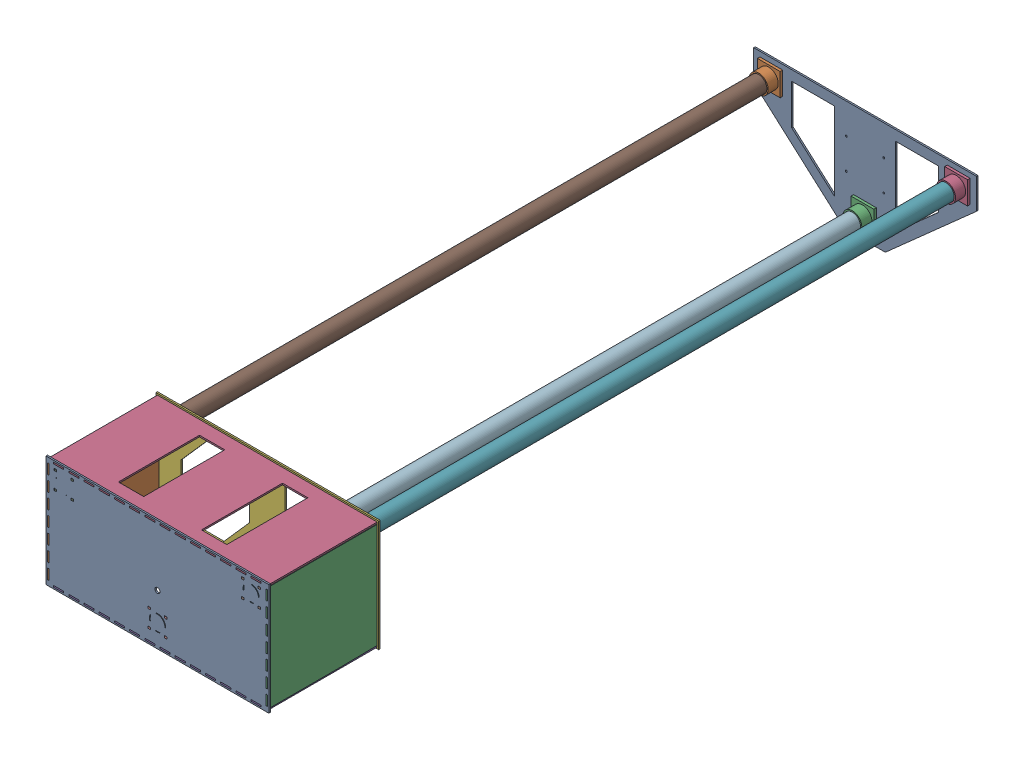
SolidWorks assembly AssembFinal, configuration Défaut. Lengths in mm.
Overall size (440.4 220 1400).
16 component instances, 8 part files, 31 mates.
Components (placement in the parent):
- Base_Boite-1: Base_Boite [Défaut] at (-19.2161 6.3272 0) size (440 220 3)
- CôtéDG_Boite-1: CôtéDG_Boite [Défaut] at (-236.2161 5.3272 -107) x (0 1 0) z (1 0 0) size (208 220 3)
- CôtéDG_Boite-2: CôtéDG_Boite [Défaut] at (197.7839 5.3272 -107) x (0 1 0) z (-1 0 0) size (208 220 3)
- Côté_Arrière_Boite-1: Côté_Arrière_Boite [Défaut] at (-19.2161 113.3272 -107) x (1 0 0) z (0 -1 0) size (434 220 3)
- Côté_Arrière_Boite_ecran-1: Côté_Arrière_Boite_ecran [Défaut] at (-19.2161 -97.6728 -107) x (1 0 0) z (0 -1 0) size (434 220 3)
- Toit_Boite-1: Toit_Boite [Défaut] at (-19.2161 6.3272 -217) size (440 220 3)
- Tube_PVC-1: Tube_PVC [Défaut] at (165.7839 84.1272 -1397) x (-0.09486 0.995491 0) z (0 0 1) size (32 32 1400)
- Support_Tube-2: Support_Tube [Défaut] at (165.7839 84.1272 0) x (1 0 0) z (0 0 -1) size (45 45 28)
- Support_Tube-3: Support_Tube [Défaut] at (-204.0161 84.1272 0) x (1 0 0) z (0 0 -1) size (45 45 28)
- Support_Tube-4: Support_Tube [Défaut] at (-19.0161 -58.8728 0) x (1 0 0) z (0 0 -1) size (45 45 28)
- Tube_PVC-2: Tube_PVC [Défaut] at (-204.0161 84.1272 -1397) x (-0.93972 0.341944 0) z (0 0 1) size (32 32 1400)
- Tube_PVC-3: Tube_PVC [Défaut] at (-19.0161 -58.8728 -1397) x (-0.80011 0.599853 0) z (0 0 1) size (32 32 1400)
- Toit_Zone_Calcul-1: Toit_Zone_Calcul [Défaut] at (-18.8161 6.3272 -1394) x (-1 0 0) z (0 0 -1) size (440 220 3)
- Support_Tube-6: Support_Tube [Défaut] at (-204.0161 84.1272 -1394) x (-1 0 0) z (0 0 1) size (45 45 28)
- Support_Tube-7: Support_Tube [Défaut] at (-19.0161 -58.8728 -1394) x (-1 0 0) z (0 0 1) size (45 45 28)
- Support_Tube-8: Support_Tube [Défaut] at (165.9839 84.1272 -1394) x (-1 0 0) z (0 0 1) size (45 45 28)
Mates (geometry in assembly coordinates):
- Coïncidente1: coincident anti-aligned: line of Base_Boite-1 through (-233.2161 106.3272 3) axis (-1 0 0); line of CôtéDG_Boite-1 through (-236.2161 106.3272 3) axis (1 0 0)
- Coïncidente2: coincident anti-aligned: line of Base_Boite-1 through (-233.2161 86.3272 3) axis (0 1 0); line of CôtéDG_Boite-1 through (-233.2161 106.3272 3) axis (0 -1 0)
- Coïncidente6: coincident anti-aligned: line of Base_Boite-1 through (194.7839 -93.6728 3) axis (1 0 0); line of CôtéDG_Boite-2 through (197.7839 -93.6728 3) axis (-1 0 0)
- Coïncidente7: coincident anti-aligned: line of Base_Boite-1 through (194.7839 -73.6728 3) axis (0 -1 0); line of CôtéDG_Boite-2 through (194.7839 -93.6728 3) axis (0 1 0)
- Coïncidente8: coincident anti-aligned: line of Base_Boite-1 through (185.7839 110.3272 3) axis (0 1 0); line of Côté_Arrière_Boite-1 through (185.7839 113.3272 3) axis (0 -1 0)
- Coïncidente10: coincident anti-aligned: line of Base_Boite-1 through (165.7839 110.3272 3) axis (1 0 0); line of Côté_Arrière_Boite-1 through (185.7839 110.3272 3) axis (-1 0 0)
- Coïncidente11: coincident aligned: line of Base_Boite-1 through (-224.2161 -97.6728 3) axis (0 -1 0); line of Côté_Arrière_Boite_ecran-1 through (-224.2161 -97.6728 3) axis (0 -1 0)
- Coïncidente12: coincident aligned: line of Base_Boite-1 through (-204.2161 -97.6728 3) axis (-1 0 0); line of Côté_Arrière_Boite_ecran-1 through (-204.2161 -97.6728 3) axis (-1 0 0)
- Coïncidente13: coincident anti-aligned: line of Côté_Arrière_Boite_ecran-1 through (-224.2161 -97.6728 -217) axis (0 -1 0); line of Toit_Boite-1 through (-224.2161 -100.6728 -217) axis (0 1 0)
- Coïncidente15: coincident aligned: line of Côté_Arrière_Boite_ecran-1 through (-224.2161 -97.6728 -217) axis (1 0 0); line of Toit_Boite-1 through (-224.2161 -97.6728 -217) axis (1 0 0)
- Coïncidente18: coincident aligned: line of Base_Boite-1 through (179.7839 65.3272 3) axis (1 0 0); line of Support_Tube-2 through (179.7839 65.3272 3) axis (1 0 0)
- Coïncidente19: coincident aligned: line of Base_Boite-1 through (179.7839 69.3272 3) axis (0 -1 0); line of Support_Tube-2 through (179.7839 69.1272 3) axis (0 -1 0)
- Coïncidente20: coincident aligned: line of Base_Boite-1 through (-190.2161 65.3272 3) axis (1 0 0); line of Support_Tube-3 through (-190.0161 65.3272 3) axis (1 0 0)
- Coïncidente21: coincident aligned: line of Base_Boite-1 through (-185.2161 65.3272 3) axis (0 1 0); line of Support_Tube-3 through (-185.2161 65.3272 3) axis (0 1 0)
- Coïncidente22: coincident aligned: line of Base_Boite-1 through (-5.2161 -77.6728 3) axis (1 0 0); line of Support_Tube-4 through (-5.0161 -77.6728 3) axis (1 0 0)
- Coïncidente23: coincident aligned: line of Base_Boite-1 through (-0.2161 -77.6728 3) axis (0 1 0); line of Support_Tube-4 through (-0.2161 -77.6728 3) axis (0 1 0)
- Coaxiale1: concentric anti-aligned: circle of Tube_PVC-1; circle of Support_Tube-2
- Coaxiale2: concentric aligned: cylinder of Support_Tube-3 through (-204.0161 84.1272 -5) axis (0 0 1) radius 16.25; circle of Tube_PVC-2
- Coaxiale3: concentric anti-aligned: circle of Support_Tube-4; circle of Tube_PVC-3
- Coïncidente24: coincident aligned: plane of Base_Boite-1 through (-19.2161 6.3272 3) normal (0 0 1); circle of Tube_PVC-1
- Coïncidente25: coincident aligned: plane of Base_Boite-1 through (-19.2161 6.3272 3) normal (0 0 1); circle of Tube_PVC-2
- Coïncidente26: coincident aligned: plane of Base_Boite-1 through (-19.2161 6.3272 3) normal (0 0 1); circle of Tube_PVC-3
- Coïncidente37: coincident anti-aligned: line of Toit_Zone_Calcul-1 through (-222.8161 65.3272 -1397) axis (1 0 0); line of Support_Tube-6 through (-218.0161 65.3272 -1397) axis (-1 0 0)
- Coïncidente38: coincident anti-aligned: line of Toit_Zone_Calcul-1 through (-222.8161 69.3272 -1397) axis (0 -1 0); line of Support_Tube-6 through (-222.8161 65.3272 -1397) axis (0 1 0)
- Coïncidente39: coincident anti-aligned: line of Toit_Zone_Calcul-1 through (-37.8161 -77.6728 -1397) axis (1 0 0); line of Support_Tube-7 through (-33.0161 -77.6728 -1397) axis (-1 0 0)
- Coïncidente40: coincident anti-aligned: line of Toit_Zone_Calcul-1 through (-37.8161 -73.6728 -1397) axis (0 -1 0); line of Support_Tube-7 through (-37.8161 -77.6728 -1397) axis (0 1 0)
- Coïncidente42: coincident anti-aligned: line of Toit_Zone_Calcul-1 through (147.1839 65.3272 -1397) axis (1 0 0); line of Support_Tube-8 through (151.9839 65.3272 -1397) axis (-1 0 0)
- Coïncidente43: coincident anti-aligned: line of Toit_Zone_Calcul-1 through (147.1839 69.3272 -1397) axis (0 -1 0); line of Support_Tube-8 through (147.1839 65.3272 -1397) axis (0 1 0)
- Coaxiale12: concentric anti-aligned: circle of Tube_PVC-2; cylinder of Support_Tube-6 through (-204.0161 84.1272 -1389) axis (0 0 -1) radius 16.25
- Coïncidente47: coincident aligned: plane of Tube_PVC-2 through (-204.0161 84.1272 -1397) normal (0 0 -1); plane of Toit_Zone_Calcul-1 through (-18.8161 6.3272 -1397) normal (0 0 -1)
- Coaxiale17: concentric aligned: circle of Tube_PVC-3; circle of Support_Tube-7
